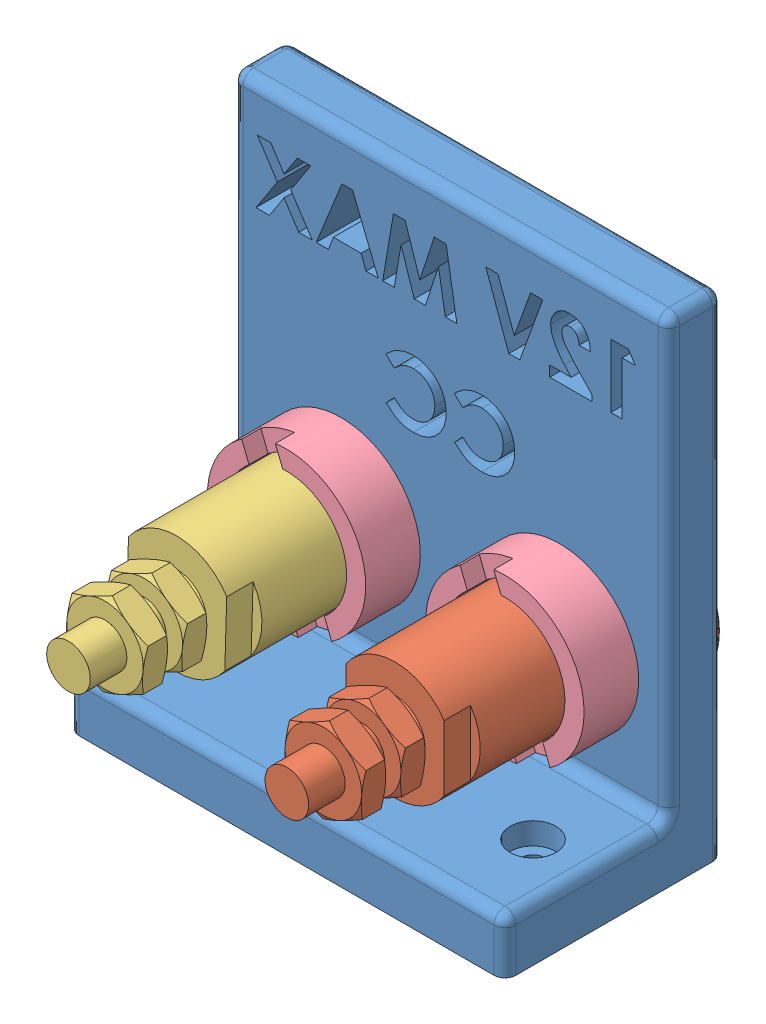
SolidWorks assembly alimentation, configuration Défaut. Lengths in mm.
Overall size (40 45 32.77).
5 component instances, 4 part files, 8 mates.
Components (placement in the parent):
- alimentation_support-1: alimentation_support [Défaut] at (-10.5748 2.0727 30) size (40 45 20)
- Douille banane noir-1: Douille banane noir [Default] at (-0.8911 1.5817 37.6675) x (1 0 0) z (0 1 0) size (14.4 32.77 14.4)
- Douille banane rouge-1: Douille banane rouge [Default] at (-20.9056 1.5913 37.6675) x (0.999557 -0.02976 0) z (0.02976 0.999557 0) size (14.4 32.77 14.4)
- Douille banane ecrou-1: Douille banane ecrou [Default] at (-20.4707 2.6475 39.6675) x (-0.923728 -0.383049 0) z (0.383049 -0.923728 0) size (14.5 5 14.5)
- Douille banane ecrou-2: Douille banane ecrou [Default] at (-0.4707 2.6475 39.6675) x (-0.923728 -0.383049 0) z (0.383049 -0.923728 0) size (14.5 5 14.5)
Mates (geometry in assembly coordinates):
- Coaxiale1: concentric anti-aligned: cylinder of support_alimentation-1 through (-20.5748 2.0727 35) axis (0 0 -1) radius 6.1; cylinder of Fiche banane rouge-1 through (-20.5748 2.0727 30) axis (0 0 1) radius 5.4
- Coaxiale2: concentric anti-aligned: cylinder of support_alimentation-1 through (-0.5748 2.0727 35) axis (0 0 -1) radius 6.1; cylinder of Fiche banane noir-1 through (-0.5748 2.0727 30) axis (0 0 1) radius 5.4
- Coïncidente1: coincident anti-aligned: plane of support_alimentation-1 through (-10.5748 2.0727 30) normal (0 0 -1); plane of Fiche banane noir-1 through (-0.5748 2.0727 30) normal (0 0 1)
- Coïncidente2: coincident anti-aligned: plane of support_alimentation-1 through (-10.5748 2.0727 30) normal (0 0 -1); plane of Fiche banane rouge-1 through (-20.5748 2.0727 30) normal (0 0 1)
- Coaxiale3: concentric aligned: cylinder of Fiche banane noir-1 through (-0.5748 2.0727 30) axis (0 0 1) radius 5.4; cylinder of Fiche banane ecrou-2 through (-0.5748 2.0727 35) axis (0 0 1) radius 5.5
- Coaxiale4: concentric aligned: cylinder of Fiche banane rouge-1 through (-20.5748 2.0727 30) axis (0 0 1) radius 5.4; cylinder of Fiche banane ecrou-1 through (-20.5748 2.0727 35) axis (0 0 1) radius 5.5
- Coïncidente3: coincident anti-aligned: plane of support_alimentation-1 through (-10.5748 2.0727 35) normal (0 0 1); plane of Fiche banane ecrou-2 through (-0.5748 2.0727 35) normal (0 0 -1)
- Coïncidente4: coincident anti-aligned: plane of support_alimentation-1 through (-10.5748 2.0727 35) normal (0 0 1); plane of Fiche banane ecrou-1 through (-20.5748 2.0727 35) normal (0 0 -1)
